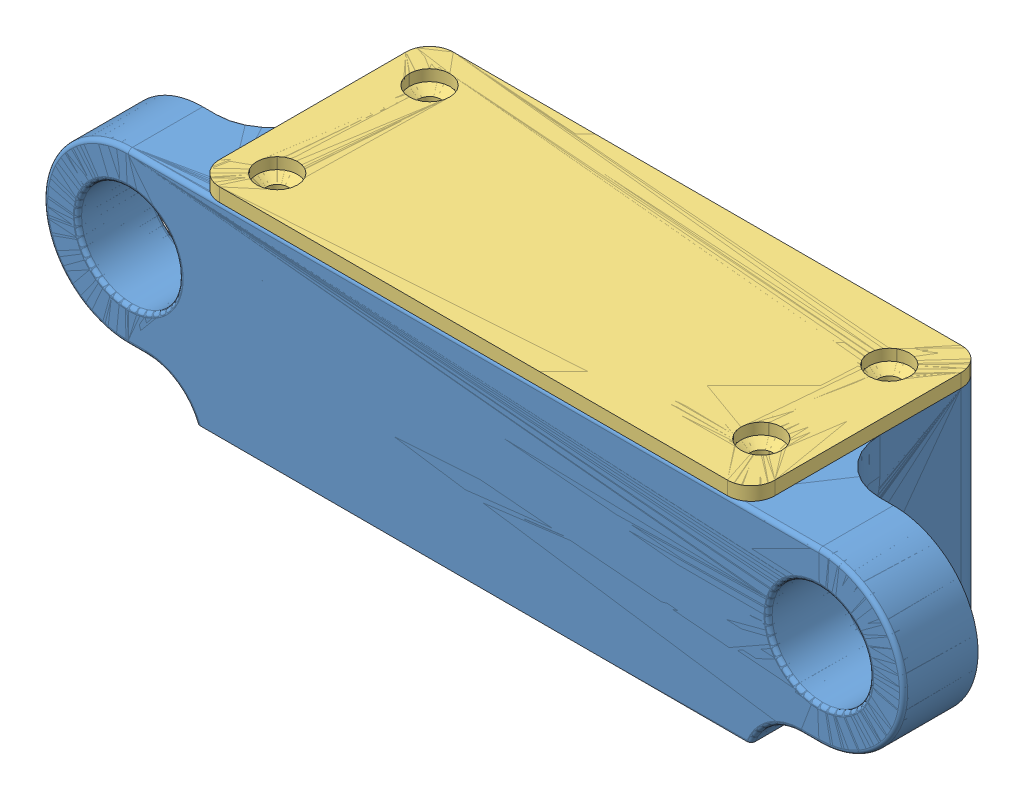
SolidWorks assembly New1SBatteryGPSAssm, configuration Default. Lengths in mm.
Overall size (127 32 34.5).
3 component instances, 3 part files, 5 mates.
Components (placement in the parent):
- TeleGPSBox-1: TeleGPSBox [Default] at (-11.1187 39.7588 87.0216) size (127 30.66 34.54)
- TeleGPSBattery-1: TeleGPSBattery [Default] at (-3.1187 57.2588 86.6834) size (60 10 30)
- TeleGPSLid-1: TeleGPSLid [Default] at (-11.1187 71.7588 56.5216) x (1 0 0) z (0 0 -1) size (82 4 34.5)
Mates (geometry in assembly coordinates):
- Coincident1: coincident anti-aligned: plane of TeleGPSBox-1 through (-3.1187 61.7588 56.5216) normal (1 0 0); plane of TeleGPSBattery-1 through (-3.1187 67.2588 86.6834) normal (-1 0 0)
- Coincident2: coincident anti-aligned: plane of TeleGPSBattery-1 through (-3.1187 57.2588 86.6834) normal (0 -1 0); plane of TeleGPSBox-1 through (-11.1187 57.2588 87.0216) normal (0 1 0)
- Coincident3: coincident anti-aligned: plane of TeleGPSBox-1 through (-11.1187 69.7588 87.0216) normal (0 1 0); plane of TeleGPSLid-1 through (-11.1187 69.7588 56.5216) normal (0 -1 0)
- Coincident5: coincident aligned: plane of TeleGPSBox-1 through (68.8813 69.7588 54.5216) normal (1 0 0); plane of TeleGPSLid-1 through (68.8813 69.7588 89.0216) normal (1 0 0)
- Coincident6: coincident aligned: plane of TeleGPSBox-1 through (-13.1187 69.7588 54.5216) normal (0 0 -1); plane of TeleGPSLid-1 through (-13.1187 69.7588 54.5216) normal (0 0 -1)
